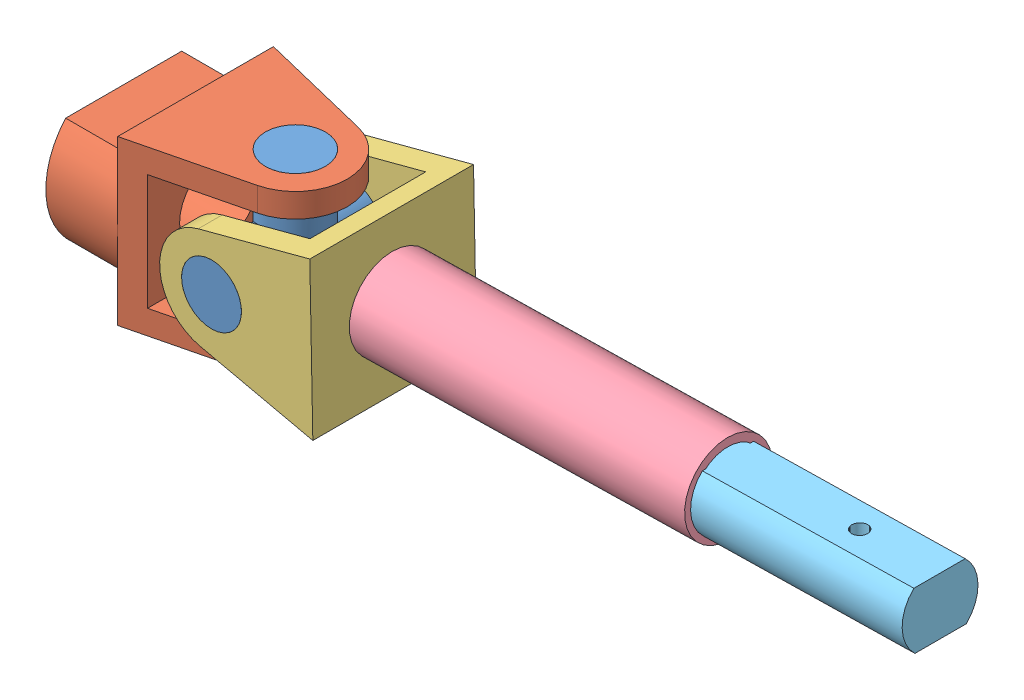
SolidWorks assembly JuntaUniversalInf, configuration Default. Lengths in mm.
Overall size (205.11 42 42).
5 component instances, 5 part files, 9 mates.
Components (placement in the parent):
- Rotula-1: Rotula [Default] at (9.2327 -3.3638 -2.5866) size (15 42 42)
- RotulaUniversalA-1: RotulaUniversalA [Default] at (-5.7673 -2.8638 -2.5866) size (56 41 39)
- RotulaUniversalB-1: RotulaUniversalB [Default] at (24.2299 -3.0734 -2.0866) x (-0.999812 -0.019365 0) z (0.019365 -0.999812 0) size (38 41 39)
- VeioRotulaInf-1: VeioRotulaInf [Default] at (-1.7653 -3.5768 -2.0866) x (0.999812 0.019365 0) z (-0.018362 0.948036 0.317632) size (92 22 22)
- VeioAjusteFordCorsa-1: VeioAjusteFordCorsa [Default] at (132.2096 -0.982 -2.0866) x (0 0 1) z (0.019365 -0.999812 0) size (19 78 14)
Mates (geometry in assembly coordinates):
- Concentric1: concentric anti-aligned: cylinder of Rotula-1 through (9.2327 17.6362 -2.5866) axis (0 1 0) radius 7.5; cylinder of RotulaUniversalA-1 through (9.2327 -23.3638 -2.5866) axis (0 -1 0) radius 7.5
- Coincident1: coincident aligned: plane of Rotula-1 through (1.7327 17.6362 -2.5866) normal (0 1 0); plane of RotulaUniversalA-1 through (-15.7673 17.6362 16.9134) normal (0 1 0)
- Concentric2: concentric anti-aligned: cylinder of Rotula-1 through (9.2327 -3.3638 -23.5866) axis (0 0 -1) radius 7.5; cylinder of RotulaUniversalB-1 through (9.2327 -3.3638 18.4134) axis (0 0 1) radius 7.5
- Coincident2: coincident aligned: plane of Rotula-1 through (1.7327 -3.3638 18.4134) normal (0 0 1); plane of RotulaUniversalB-1 through (34.6056 -22.3761 18.4134) normal (0 0 1)
- Concentric3: concentric aligned: cylinder of RotulaUniversalB-1 through (-3.7649 -3.6156 -2.0866) axis (0.999812 0.019365 0) radius 10; cylinder of VeioRotulaInf-1 through (106.4446 -1.481 -2.0866) axis (0.999812 0.019365 0) radius 10
- Coincident3: coincident anti-aligned: plane of RotulaUniversalB-1 through (34.6056 -22.3761 -15.0866) normal (0.999812 0.019365 0); plane of VeioRotulaInf-1 through (34.1665 0.296 -11.5688) normal (-0.999812 -0.019365 0)
- Concentric4: concentric anti-aligned: cylinder of VeioRotulaInf-1 through (106.4446 -1.481 -2.0866) axis (0.999812 0.019365 0) radius 9; cylinder of VeioAjusteFordCorsa-1 through (118.2122 -1.2531 -2.0866) axis (-0.999812 -0.019365 0) radius 9
- Coincident4: coincident anti-aligned: plane of VeioRotulaInf-1 through (118.1446 2.2402 -12.517) normal (0.999812 0.019365 0); plane of VeioAjusteFordCorsa-1 through (118.2122 -1.2531 -2.0866) normal (-0.999812 -0.019365 0)
- Parallel1: parallel: line of RotulaUniversalB-1 through (33.8504 16.6166 -22.5866) axis (0 0 1); plane of VeioAjusteFordCorsa-1 through (93.0814 5.2615 -8.5092) normal (-0.019365 0.999812 0)
